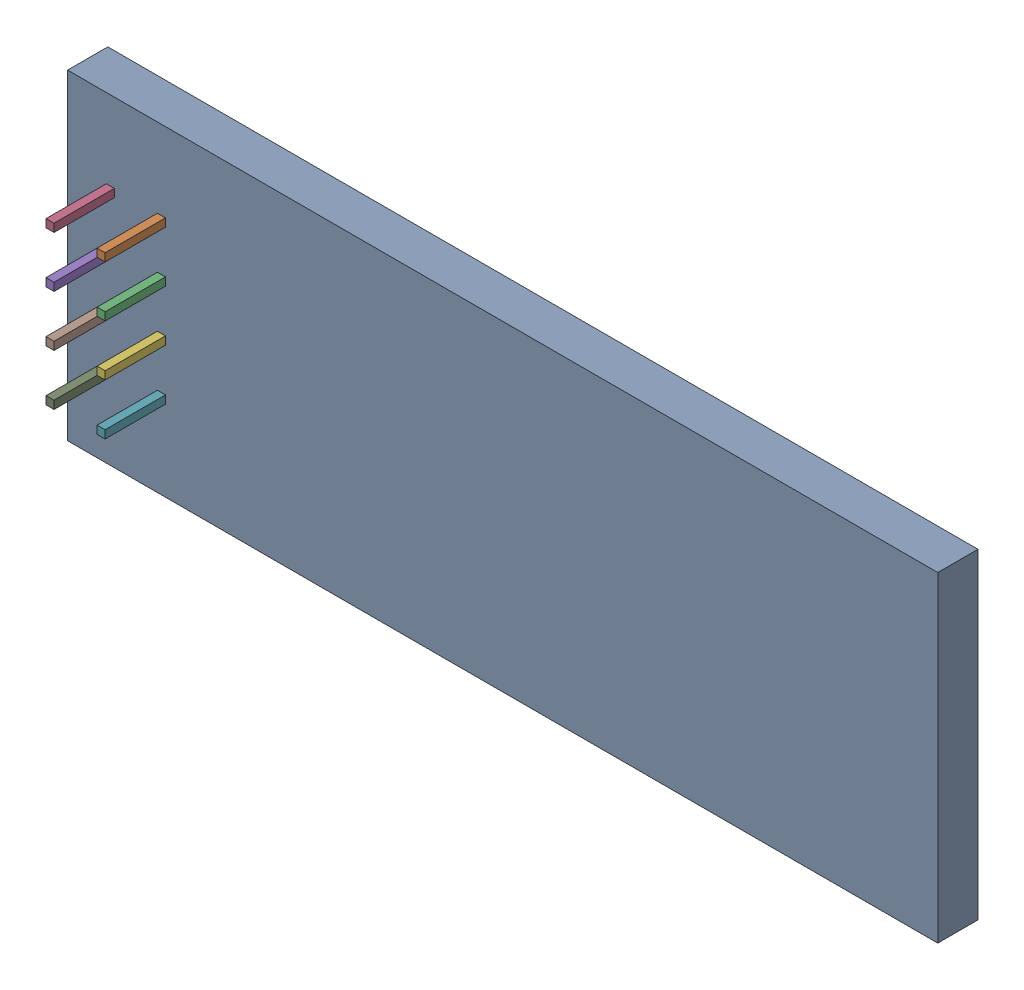
SolidWorks assembly U3-1, configuration Default. Lengths in mm.
Overall size (43.25 15.95 5.5).
18 component instances, 2 part files, 0 mates.
Components (placement in the parent):
- 959206080-1-1: 959206080-1 [Default] at (102.177 84.441 -2.3912) size (43.25 15.95 2)
  - Extruded-37-1: Extruded-37 [Default] at origin size (43.25 15.95 2)
- 959205944-1-1: 959205944-1 [Default] at (85.217 88.291 -2.8912) size (0.4 0.4 5.5)
  - Extruded-38-1: Extruded-38 [Default] at origin size (0.4 0.4 5.5)
- 959205944-1-2: 959205944-1 [Default] at (85.217 85.751 -2.8912) size (0.4 0.4 5.5)
  - Extruded-38-1: Extruded-38 [Default] at origin size (0.4 0.4 5.5)
- 959205944-1-3: 959205944-1 [Default] at (82.677 88.291 -2.8912) size (0.4 0.4 5.5)
  - Extruded-38-1: Extruded-38 [Default] at origin size (0.4 0.4 5.5)
- 959205944-1-4: 959205944-1 [Default] at (82.677 85.751 -2.8912) size (0.4 0.4 5.5)
  - Extruded-38-1: Extruded-38 [Default] at origin size (0.4 0.4 5.5)
- 959205944-1-5: 959205944-1 [Default] at (85.217 83.211 -2.8912) size (0.4 0.4 5.5)
  - Extruded-38-1: Extruded-38 [Default] at origin size (0.4 0.4 5.5)
- 959205944-1-6: 959205944-1 [Default] at (85.217 80.671 -2.8912) size (0.4 0.4 5.5)
  - Extruded-38-1: Extruded-38 [Default] at origin size (0.4 0.4 5.5)
- 959205944-1-7: 959205944-1 [Default] at (82.677 83.211 -2.8912) size (0.4 0.4 5.5)
  - Extruded-38-1: Extruded-38 [Default] at origin size (0.4 0.4 5.5)
- 959205944-1-8: 959205944-1 [Default] at (82.677 80.671 -2.8912) size (0.4 0.4 5.5)
  - Extruded-38-1: Extruded-38 [Default] at origin size (0.4 0.4 5.5)
